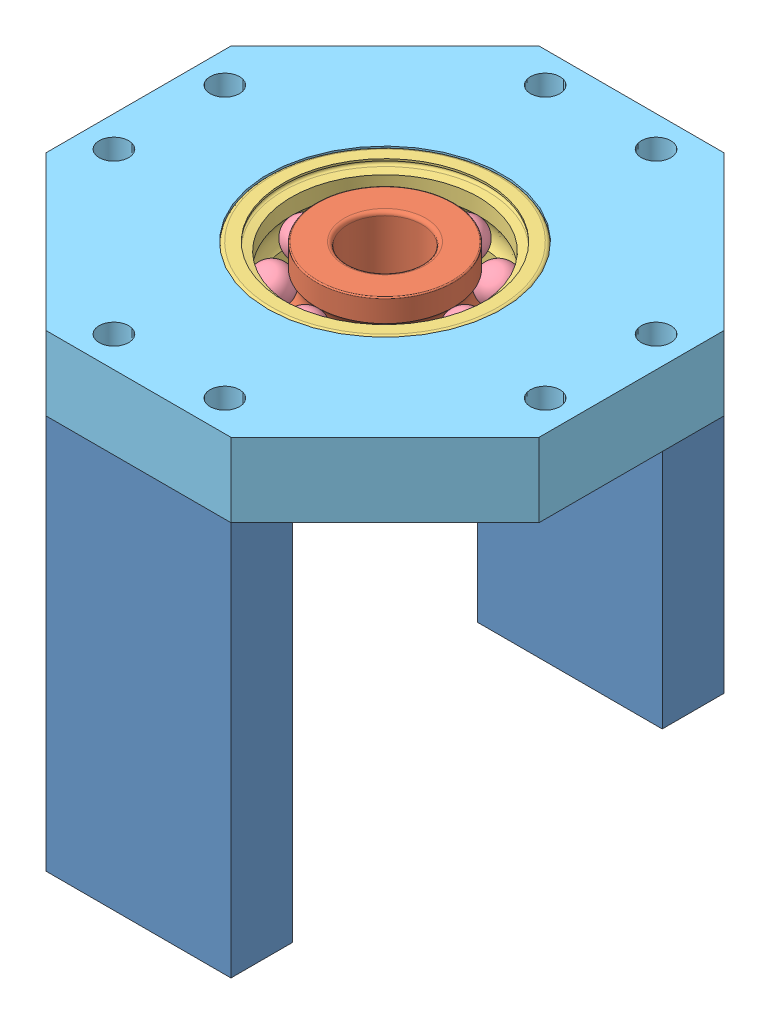
SolidWorks assembly sup_polia, configuration Default. Lengths in mm.
Overall size (40 38 40).
14 component instances, 5 part files, 7 mates.
Components (placement in the parent):
- sup_alt_polia-1: sup_alt_polia [Default] at (-11.1086 1.6331 17.123) size (15 32 5)
- sup_alt_polia-3: sup_alt_polia [Default] at (-11.1086 1.6331 -17.877) size (15 32 5)
- 626-1: 626 [Default] at (-11.1086 7.6331 -0.377) x (0 -1 0) z (0 0 1) size (6 19 19)
  - 626_PART1-1: 626_PART1 [Default] at origin size (6 11.1 11.1)
  - 626_PART2-1: 626_PART2 [Default] at origin size (6 19 19)
  - 626_PART3-1: 626_PART3 [Default] at origin size (3 3 3)
  - 626_PART3-2: 626_PART3 [Default] x (1 0 0) z (0 0.707107 0.707107) size (3 3 3)
  - 626_PART3-3: 626_PART3 [Default] x (1 0 0) z (0 1 0) size (3 3 3)
  - 626_PART3-4: 626_PART3 [Default] x (1 0 0) z (0 0.707107 -0.707107) size (3 3 3)
  - 626_PART3-5: 626_PART3 [Default] x (1 0 0) z (0 0 -1) size (3 3 3)
  - 626_PART3-6: 626_PART3 [Default] x (1 0 0) z (0 -0.707107 -0.707107) size (3 3 3)
  - 626_PART3-7: 626_PART3 [Default] x (1 0 0) z (0 -1 0) size (3 3 3)
  - 626_PART3-8: 626_PART3 [Default] x (1 0 0) z (0 -0.707107 0.707107) size (3 3 3)
- sup_veio_polia_polia-1: sup_veio_polia_polia [Default] at (-31.1086 7.6331 19.623) size (40 6 40)
Mates (geometry in assembly coordinates):
- Coincident14: coincident aligned: plane of sup_alt_polia-1 through (-3.6086 1.6331 14.623) normal (0 1 0); plane of sup_alt_polia-3 through (-3.6086 1.6331 -20.377) normal (0 1 0)
- Concentric1: concentric anti-aligned: cylinder of 626-1/626_PART2-1 through (-11.1086 1.9331 -0.377) axis (0 -1 0) radius 9.5; cylinder of sup_veio_polia_polia-1 through (-11.1086 1.6331 -0.377) axis (0 1 0) radius 9.5
- Coincident15: coincident aligned: plane of 626-1/626_PART2-1 through (-1.9086 7.6331 -0.377) normal (0 1 0); plane of sup_veio_polia_polia-1 through (-31.1086 7.6331 -20.377) normal (0 1 0)
- Coincident16: coincident anti-aligned: line of sup_alt_polia-3 through (-3.6086 -30.3669 -20.377) axis (0 1 0); line of sup_veio_polia_polia-1 through (-3.6086 7.6331 -20.377) axis (0 -1 0)
- Coincident17: coincident anti-aligned: plane of sup_alt_polia-3 through (-3.6086 1.6331 -20.377) normal (0 1 0); plane of sup_veio_polia_polia-1 through (-31.1086 1.6331 -20.377) normal (0 -1 0)
- Coincident18: coincident anti-aligned: plane of sup_alt_polia-1 through (-3.6086 1.6331 14.623) normal (0 1 0); plane of sup_veio_polia_polia-1 through (-31.1086 1.6331 -20.377) normal (0 -1 0)
- Coincident19: coincident anti-aligned: line of sup_alt_polia-1 through (-18.6086 -30.3669 19.623) axis (0 1 0); line of sup_veio_polia_polia-1 through (-18.6086 7.6331 19.623) axis (0 -1 0)
